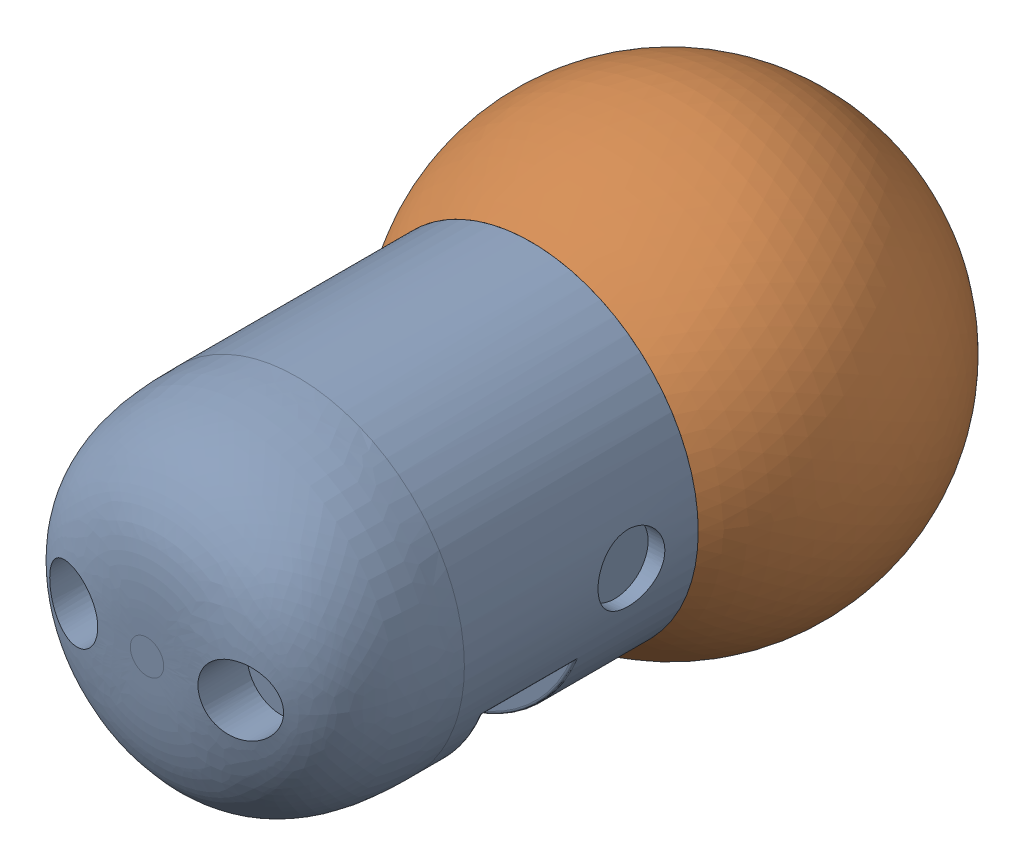
SolidWorks assembly body hand head, configuration Default. Lengths in mm.
Overall size (260.45 260.45 444.44).
4 component instances, 2 part files, 4 mates.
Components (placement in the parent):
- pill size new design-1: pill size new design [Default] at (-27.3336 94.3626 77.2065) size (203.94 203.94 230.8)
- Hand Assembly-1: Hand Assembly [Default] at (-153.2394 20.7936 288.9279) x (1 0 0) z (0 0.806989 0.590566) (suppressed, hidden)
- head round-1: head round [Default] at (-27.3336 94.3626 143.7904) x (1 0 0) z (0 1 0) size (260.45 213.64 260.45)
- Hand Assembly-3: Hand Assembly [Default] at (98.5721 95.5176 343.6119) x (-1 0 0) z (0 -0.806989 -0.590566) (suppressed, hidden)
Mates (geometry in assembly coordinates):
- Coincident1: coincident anti-aligned: plane of pill size new design-1 through (-117.3336 94.3626 267.2065) normal (-1 0 0); plane of hand with ball-1/hand-1 through (-117.3336 94.3626 267.2065) normal (1 0 0)
- Concentric1: concentric aligned: cylinder of pill size new design-1 through (-117.3336 94.3626 267.2065) axis (-1 0 0) radius 20; cylinder of hand with ball-1/hand-1 through (-117.3336 94.3626 267.2065) axis (-1 0 0) radius 20
- Coincident2: coincident anti-aligned: plane of pill size new design-1 through (-27.3336 -155.6374 227.2065) normal (0 0 -1); plane of head round-1 through (-27.3336 94.3626 227.2065) normal (0 0 1)
- Coincident3: coincident anti-aligned: circle of pill size new design-1; circle of head round-1
